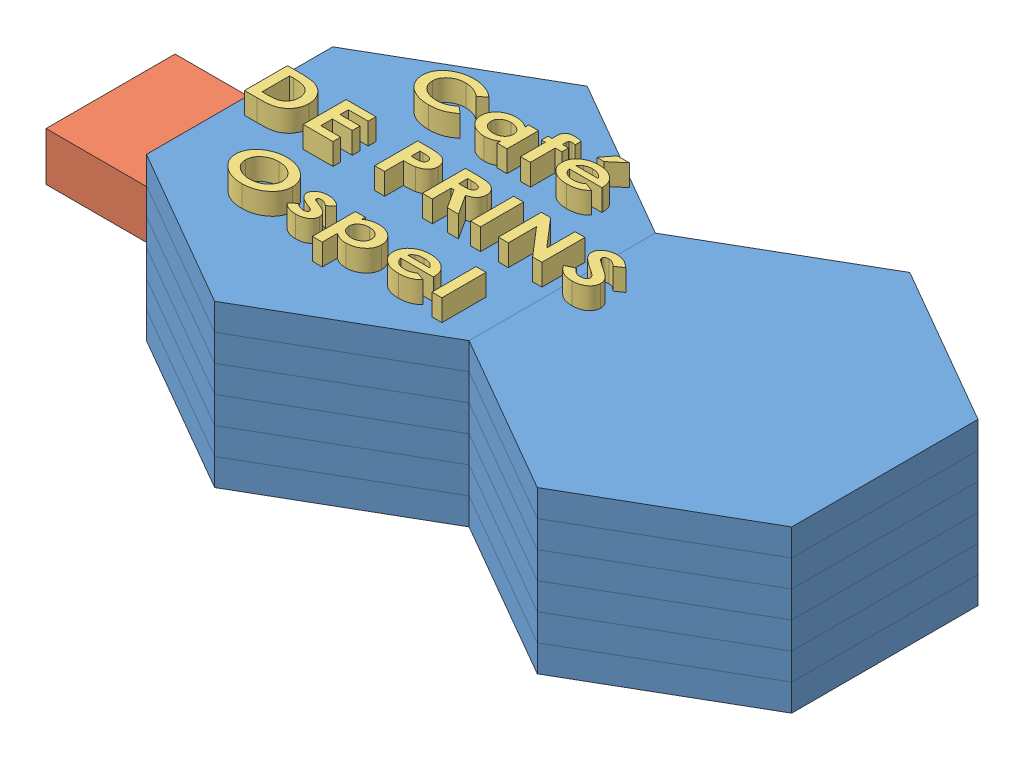
SolidWorks assembly Cafe de prins usb stick, configuration Default. Lengths in mm.
Overall size (72 17 34.64).
14 component instances, 3 part files, 37 mates.
Components (placement in the parent):
- cafe de prins munt-1: cafe de prins munt [Default] at (10.815 21.7001 25.2452) size (30 2.5 34.64)
- cafe de prins munt-3: cafe de prins munt [Default] at (10.815 24.2001 25.2452) size (30 2.5 34.64)
- cafe de prins munt-4: cafe de prins munt [Default] at (10.815 26.7001 25.2452) size (30 2.5 34.64)
- cafe de prins munt-5: cafe de prins munt [Default] at (10.815 29.2001 25.2452) size (30 2.5 34.64)
- cafe de prins munt-6: cafe de prins munt [Default] at (10.815 34.2001 25.2452) size (30 2.5 34.64)
- cafe de prins munt-8: cafe de prins munt [Default] at (10.815 31.7001 25.2452) size (30 2.5 34.64)
- cafe de prins munt-14: cafe de prins munt [Default] at (40.815 26.7001 25.2452) size (30 2.5 34.64)
- cafe de prins munt-15: cafe de prins munt [Default] at (40.815 21.7001 25.2452) size (30 2.5 34.64)
- cafe de prins munt-16: cafe de prins munt [Default] at (40.815 34.2001 25.2452) size (30 2.5 34.64)
- cafe de prins munt-17: cafe de prins munt [Default] at (40.815 31.7001 25.2452) size (30 2.5 34.64)
- cafe de prins munt-18: cafe de prins munt [Default] at (40.815 29.2001 25.2452) size (30 2.5 34.64)
- cafe de prins munt-19: cafe de prins munt [Default] at (40.815 24.2001 25.2452) size (30 2.5 34.64)
- ijzergedeelte usb-1: ijzergedeelte usb [Default] at (-10.185 27.9501 25.2452) size (12 4.5 12)
- tekst cafe-1: tekst cafe [Default] at (13.9066 35.4501 24.3318) size (32.09 2 20.67)
Mates (geometry in assembly coordinates):
- Coincident1: coincident: plane of cafe de prins munt-1 through (10.815 22.9501 25.2452) normal (0 1 0); plane of cafe de prins munt-3 through (10.815 22.9501 25.2452) normal (0 -1 0)
- Coincident2: coincident: plane of cafe de prins munt-1 through (10.815 22.9501 42.5657) normal (0.5 0 0.866025); plane of cafe de prins munt-3 through (10.815 25.4501 42.5657) normal (0.5 0 0.866025)
- Coincident3: coincident: line of cafe de prins munt-1 through (-4.185 22.9501 33.9055) axis (0.866025 0 0.5); plane of cafe de prins munt-3 through (-4.185 25.4501 33.9055) normal (-0.5 0 0.866025)
- Coincident4: coincident: plane of cafe de prins munt-3 through (10.815 25.4501 25.2452) normal (0 1 0); plane of cafe de prins munt-4 through (10.815 25.4501 25.2452) normal (0 -1 0)
- Coincident5: coincident: line of cafe de prins munt-3 through (25.815 25.4501 33.9055) axis (0 -1 0); line of cafe de prins munt-4 through (25.815 27.9501 33.9055) axis (0 -1 0)
- Coincident6: coincident: plane of cafe de prins munt-3 through (-4.185 25.4501 33.9055) normal (-0.5 0 0.866025); plane of cafe de prins munt-4 through (-4.185 27.9501 33.9055) normal (-0.5 0 0.866025)
- Coincident7: coincident: plane of cafe de prins munt-4 through (10.815 27.9501 25.2452) normal (0 1 0); plane of cafe de prins munt-5 through (10.815 27.9501 25.2452) normal (0 -1 0)
- Coincident8: coincident: plane of cafe de prins munt-4 through (10.815 27.9501 42.5657) normal (0.5 0 0.866025); plane of cafe de prins munt-5 through (10.815 30.4501 42.5657) normal (0.5 0 0.866025)
- Coincident9: coincident: plane of cafe de prins munt-4 through (25.815 27.9501 16.585) normal (0.5 0 -0.866025); plane of cafe de prins munt-5 through (25.815 30.4501 16.585) normal (0.5 0 -0.866025)
- Coincident10: coincident: plane of cafe de prins munt-5 through (10.815 30.4501 25.2452) normal (0 1 0); plane of cafe de prins munt-8 through (10.815 30.4501 25.2452) normal (0 -1 0)
- Coincident11: coincident: plane of cafe de prins munt-5 through (10.815 30.4501 42.5657) normal (0.5 0 0.866025); plane of cafe de prins munt-8 through (10.815 32.9501 42.5657) normal (0.5 0 0.866025)
- Coincident12: coincident: plane of cafe de prins munt-5 through (-4.185 30.4501 33.9055) normal (-0.5 0 0.866025); plane of cafe de prins munt-8 through (-4.185 32.9501 33.9055) normal (-0.5 0 0.866025)
- Coincident13: coincident: plane of cafe de prins munt-6 through (10.815 32.9501 25.2452) normal (0 -1 0); plane of cafe de prins munt-8 through (10.815 32.9501 25.2452) normal (0 1 0)
- Coincident14: coincident: plane of cafe de prins munt-6 through (10.815 35.4501 42.5657) normal (0.5 0 0.866025); plane of cafe de prins munt-8 through (10.815 32.9501 42.5657) normal (0.5 0 0.866025)
- Coincident15: coincident: plane of cafe de prins munt-6 through (25.815 35.4501 33.9055) normal (1 0 0); line of cafe de prins munt-8 through (25.815 32.9501 33.9055) axis (0 0 -1)
- Coincident16: coincident: line of cafe de prins munt-14 through (55.815 27.9501 33.9055) axis (0 -1 0); line of cafe de prins munt-19 through (55.815 25.4501 33.9055) axis (0 -1 0)
- Coincident17: coincident: line of cafe de prins munt-15 through (25.815 22.9501 33.9055) axis (0.866025 0 0.5); plane of cafe de prins munt-19 through (25.815 25.4501 33.9055) normal (-0.5 0 0.866025)
- Coincident18: coincident: plane of cafe de prins munt-14 through (40.815 27.9501 42.5657) normal (0.5 0 0.866025); plane of cafe de prins munt-18 through (40.815 30.4501 42.5657) normal (0.5 0 0.866025)
- Coincident19: coincident: plane of cafe de prins munt-15 through (40.815 22.9501 42.5657) normal (0.5 0 0.866025); plane of cafe de prins munt-19 through (40.815 25.4501 42.5657) normal (0.5 0 0.866025)
- Coincident20: coincident: plane of cafe de prins munt-14 through (40.815 25.4501 25.2452) normal (0 -1 0); plane of cafe de prins munt-19 through (40.815 25.4501 25.2452) normal (0 1 0)
- Coincident21: coincident: plane of cafe de prins munt-15 through (40.815 22.9501 25.2452) normal (0 1 0); plane of cafe de prins munt-19 through (40.815 22.9501 25.2452) normal (0 -1 0)
- Coincident22: coincident: plane of cafe de prins munt-17 through (40.815 30.4501 25.2452) normal (0 -1 0); plane of cafe de prins munt-18 through (40.815 30.4501 25.2452) normal (0 1 0)
- Coincident23: coincident: plane of cafe de prins munt-17 through (25.815 32.9501 33.9055) normal (-0.5 0 0.866025); plane of cafe de prins munt-18 through (25.815 30.4501 33.9055) normal (-0.5 0 0.866025)
- Coincident24: coincident: plane of cafe de prins munt-14 through (25.815 27.9501 33.9055) normal (-0.5 0 0.866025); plane of cafe de prins munt-19 through (25.815 25.4501 33.9055) normal (-0.5 0 0.866025)
- Coincident25: coincident: plane of cafe de prins munt-14 through (40.815 27.9501 25.2452) normal (0 1 0); plane of cafe de prins munt-18 through (40.815 27.9501 25.2452) normal (0 -1 0)
- Coincident26: coincident: plane of cafe de prins munt-14 through (55.815 27.9501 16.585) normal (0.5 0 -0.866025); plane of cafe de prins munt-18 through (55.815 30.4501 16.585) normal (0.5 0 -0.866025)
- Coincident27: coincident: plane of cafe de prins munt-17 through (40.815 32.9501 42.5657) normal (0.5 0 0.866025); plane of cafe de prins munt-18 through (40.815 30.4501 42.5657) normal (0.5 0 0.866025)
- Coincident28: coincident: plane of cafe de prins munt-16 through (40.815 32.9501 25.2452) normal (0 -1 0); plane of cafe de prins munt-17 through (40.815 32.9501 25.2452) normal (0 1 0)
- Coincident29: coincident: plane of cafe de prins munt-16 through (40.815 35.4501 42.5657) normal (0.5 0 0.866025); plane of cafe de prins munt-17 through (40.815 32.9501 42.5657) normal (0.5 0 0.866025)
- Coincident30: coincident: plane of cafe de prins munt-16 through (55.815 35.4501 33.9055) normal (1 0 0); line of cafe de prins munt-17 through (55.815 32.9501 33.9055) axis (0 0 -1)
- Coincident31: coincident: plane of cafe de prins munt-5 through (25.815 30.4501 33.9055) normal (1 0 0); plane of cafe de prins munt-18 through (25.815 30.4501 16.585) normal (-1 0 0)
- Coincident32: coincident: plane of cafe de prins munt-1 through (10.815 20.4501 25.2452) normal (0 -1 0); plane of cafe de prins munt-15 through (40.815 20.4501 25.2452) normal (0 -1 0)
- Coincident33: coincident: line of cafe de prins munt-5 through (25.815 30.4501 16.585) axis (0 -1 0); line of cafe de prins munt-14 through (25.815 27.9501 16.585) axis (0 -1 0)
- Coincident34: coincident: plane of cafe de prins munt-5 through (-4.185 30.4501 16.585) normal (-1 0 0); plane of ijzergedeelte usb-1 through (-4.185 30.2001 19.2452) normal (1 0 0)
- Coincident35: coincident: plane of cafe de prins munt-1 through (10.815 21.7001 25.2452) normal (0 0 1); plane of ijzergedeelte usb-1 through (-10.185 27.9501 25.2452) normal (0 0 1)
- Coincident36: coincident: line of cafe de prins munt-4 through (-4.185 27.9501 33.9055) axis (0.866025 0 0.5); plane of ijzergedeelte usb-1 through (-10.185 27.9501 25.2452) normal (0 1 0)
- Coincident37: coincident: plane of cafe de prins munt-6 through (10.815 35.4501 25.2452) normal (0 1 0); plane of tekst cafe-1 through (13.9066 35.4501 24.3318) normal (0 -1 0)
